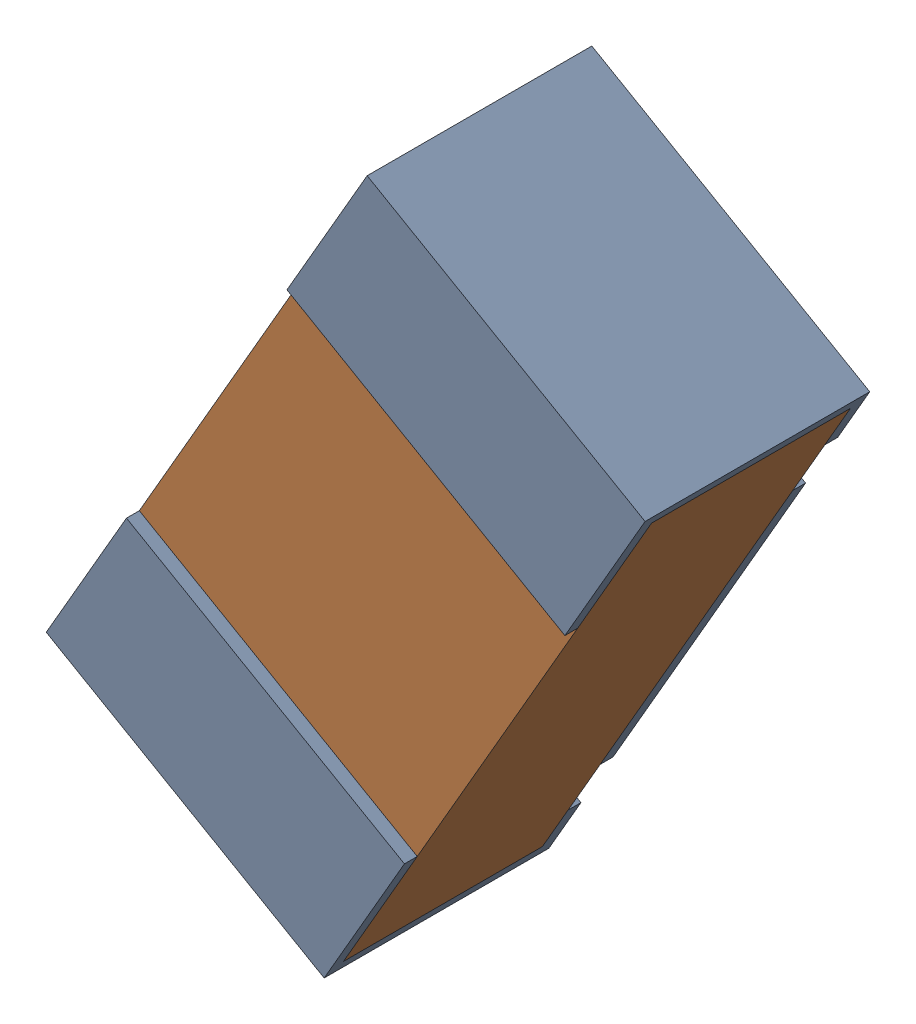
SolidWorks assembly R16, configuration Default. Lengths in mm.
Overall size (0.93 1.12 0.35).
3 component instances, 2 part files, 0 mates.
Components (placement in the parent):
- R16-subassembly-1-1: R16-subassembly-1 [Default] at (4.2539 -4.1271 -1.6307) x (0.5 0.866025 0) z (-0.866025 0.5 0) size (1 0.35 0.5)
  - 0402 resistor-1: 0402 resistor [Default] at origin size (1 0.35 0.5)
  - 0402 resistor-1-1: 0402 resistor-1 [Default] at origin size (0.96 0.31 0.5)
